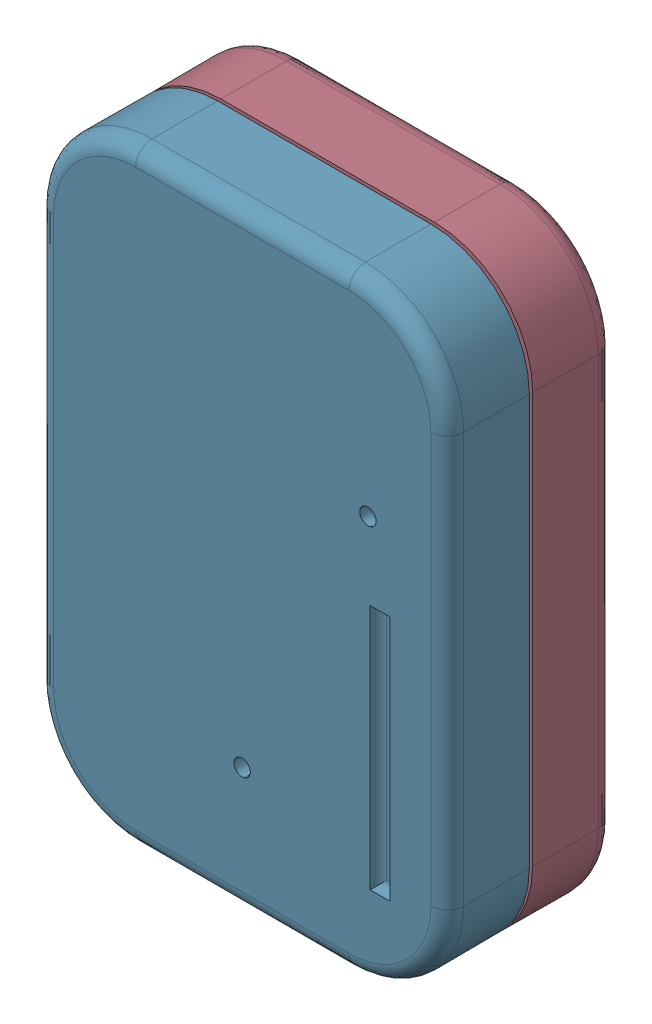
SolidWorks assembly ASSEMBLY, configuration Default. Lengths in mm.
Overall size (24.97 36.97 10.2).
67 component instances, 15 part files, 0 mates.
Components (placement in the parent):
- 3D_End Device_2025-10-05.step-1: 3D_End Device_2025-10-05.step [Default] at (-3.1574 34.3735 25.9804) size (20.97 32.97 10.2)
  - L1~L0402~L0402_L1.0-W0.5-H0.5_BEAD~bX66.step-1: L1~L0402~L0402_L1.0-W0.5-H0.5_BEAD~bX66.step [Default] at (9.437 -12.392 1.6001) x (0 1 0) z (0 0 1) size (0.76 0.76 0.76)
    - L2~L0402~L0402_L1.0-W0.5-H0.5_BEAD~bX66.step-1: L2~L0402~L0402_L1.0-W0.5-H0.5_BEAD~bX66.step [Default] at origin size (0.76 0.76 0.76)
  - X1~CRYSTAL-SMD_4P-L3.2-W2.5-BL~CRYSTAL-SMD_4P-L3.2-W2.5-BL_SIT8008BI~bX66.step-1: X1~CRYSTAL-SMD_4P-L3.2-W2.5-BL~CRYSTAL-SMD_4P-L3.2-W2.5-BL_SIT8008BI~bX66.step [Default] at (13.7334 -14.7376 1.6001) x (0 1 0) z (0 0 1) size (0.76 0.76 0.76)
    - CRYSTAL-SMD_4P-L3.2-W2.5-BL~CRYSTAL-SMD_4P-L3.2-W2.5-BL_SIT8008BI~bX66.step-1: CRYSTAL-SMD_4P-L3.2-W2.5-BL~CRYSTAL-SMD_4P-L3.2-W2.5-BL_SIT8008BI~bX66.step [Default] at origin size (0.76 0.76 0.76)
  - R1~R0402~R0402_L1.0-W0.5-H0.4~bX66.step-1: R1~R0402~R0402_L1.0-W0.5-H0.4~bX66.step [Default] at (4.7194 -17.5106 1.6001) x (0 1 0) z (0 0 1) size (0.76 0.76 0.76)
    - R5~R0402~R0402_L1.0-W0.5-H0.4~bX66.step-1: R5~R0402~R0402_L1.0-W0.5-H0.4~bX66.step [Default] at origin size (0.76 0.76 0.76)
  - BT1~BAT-SMD_MY-2032-12~BAT-SMD_MY-2032-12~bX66.step-1: BT1~BAT-SMD_MY-2032-12~BAT-SMD_MY-2032-12~bX66.step [Default] at (10.502 -19.933 0) x (0 1 0) z (0 0 -1) size (24.1 15.69 3.6)
    - BAT-SMD_MY-2032-12~BAT-SMD_MY-2032-12~bX66.step-1: BAT-SMD_MY-2032-12~BAT-SMD_MY-2032-12~bX66.step [Default] at origin size (24.1 15.69 3.6)
  - C1~C0402~C0402_L1.0-W0.5-H0.5~bX66.step-1: C1~C0402~C0402_L1.0-W0.5-H0.5~bX66.step [Default] at (14.0762 -17.6973 1.6001) size (1 0.5 0.5)
    - C0402~C0402_L1.0-W0.5-H0.5~bX66.step-1: C0402~C0402_L1.0-W0.5-H0.5~bX66.step [Default] at origin size (1 0.5 0.5)
  - C1~C0402~C0402_L1.0-W0.5-H0.5~bX66.step-2: C1~C0402~C0402_L1.0-W0.5-H0.5~bX66.step [Default] at (13.4642 -11.9342 1.6001) x (-1 0 0) z (0 0 1) size (1 0.5 0.5)
    - C0402~C0402_L1.0-W0.5-H0.5~bX66.step-1: C0402~C0402_L1.0-W0.5-H0.5~bX66.step [Default] at origin size (1 0.5 0.5)
  - C1~C0402~C0402_L1.0-W0.5-H0.5~bX66.step-3: C1~C0402~C0402_L1.0-W0.5-H0.5~bX66.step [Default] at (9.4954 -16.5416 1.6001) x (0 1 0) z (0 0 1) size (1 0.5 0.5)
    - C0402~C0402_L1.0-W0.5-H0.5~bX66.step-1: C0402~C0402_L1.0-W0.5-H0.5~bX66.step [Default] at origin size (1 0.5 0.5)
  - C1~C0402~C0402_L1.0-W0.5-H0.5~bX66.step-4: C1~C0402~C0402_L1.0-W0.5-H0.5~bX66.step [Default] at (8.3014 -16.5416 1.6001) x (0 1 0) z (0 0 1) size (1 0.5 0.5)
    - C0402~C0402_L1.0-W0.5-H0.5~bX66.step-1: C0402~C0402_L1.0-W0.5-H0.5~bX66.step [Default] at origin size (1 0.5 0.5)
  - C1~C0402~C0402_L1.0-W0.5-H0.5~bX66.step-5: C1~C0402~C0402_L1.0-W0.5-H0.5~bX66.step [Default] at (10.6082 -12.3932 1.6001) x (0 -1 0) z (0 0 1) size (1 0.5 0.5)
    - C0402~C0402_L1.0-W0.5-H0.5~bX66.step-1: C0402~C0402_L1.0-W0.5-H0.5~bX66.step [Default] at origin size (1 0.5 0.5)
  - C1~C0402~C0402_L1.0-W0.5-H0.5~bX66.step-6: C1~C0402~C0402_L1.0-W0.5-H0.5~bX66.step [Default] at (8.8094 -10.4456 1.6001) x (-1 0 0) z (0 0 1) size (1 0.5 0.5)
    - C0402~C0402_L1.0-W0.5-H0.5~bX66.step-1: C0402~C0402_L1.0-W0.5-H0.5~bX66.step [Default] at origin size (1 0.5 0.5)
  - C1~C0402~C0402_L1.0-W0.5-H0.5~bX66.step-7: C1~C0402~C0402_L1.0-W0.5-H0.5~bX66.step [Default] at (8.802 -9.217 1.6001) x (-1 0 0) z (0 0 1) size (1 0.5 0.5)
    - C0402~C0402_L1.0-W0.5-H0.5~bX66.step-1: C0402~C0402_L1.0-W0.5-H0.5~bX66.step [Default] at origin size (1 0.5 0.5)
  - C1~C0402~C0402_L1.0-W0.5-H0.5~bX66.step-8: C1~C0402~C0402_L1.0-W0.5-H0.5~bX66.step [Default] at (3.9665 -14.0976 1.6001) size (1 0.5 0.5)
    - C0402~C0402_L1.0-W0.5-H0.5~bX66.step-1: C0402~C0402_L1.0-W0.5-H0.5~bX66.step [Default] at origin size (1 0.5 0.5)
  - C1~C0402~C0402_L1.0-W0.5-H0.5~bX66.step-9: C1~C0402~C0402_L1.0-W0.5-H0.5~bX66.step [Default] at (3.9665 -8.2555 1.6001) size (1 0.5 0.5)
    - C0402~C0402_L1.0-W0.5-H0.5~bX66.step-1: C0402~C0402_L1.0-W0.5-H0.5~bX66.step [Default] at origin size (1 0.5 0.5)
  - C1~C0402~C0402_L1.0-W0.5-H0.5~bX66.step-10: C1~C0402~C0402_L1.0-W0.5-H0.5~bX66.step [Default] at (3.722 -23.187 1.6001) x (-1 0 0) z (0 0 1) size (1 0.5 0.5)
    - C0402~C0402_L1.0-W0.5-H0.5~bX66.step-1: C0402~C0402_L1.0-W0.5-H0.5~bX66.step [Default] at origin size (1 0.5 0.5)
  - C1~C0402~C0402_L1.0-W0.5-H0.5~bX66.step-11: C1~C0402~C0402_L1.0-W0.5-H0.5~bX66.step [Default] at (13.7192 -24.8884 1.6001) x (-1 0 0) z (0 0 1) size (1 0.5 0.5)
    - C0402~C0402_L1.0-W0.5-H0.5~bX66.step-1: C0402~C0402_L1.0-W0.5-H0.5~bX66.step [Default] at origin size (1 0.5 0.5)
  - C1~C0402~C0402_L1.0-W0.5-H0.5~bX66.step-12: C1~C0402~C0402_L1.0-W0.5-H0.5~bX66.step [Default] at (13.6354 -19.2086 1.6001) x (-1 0 0) z (0 0 1) size (1 0.5 0.5)
    - C0402~C0402_L1.0-W0.5-H0.5~bX66.step-1: C0402~C0402_L1.0-W0.5-H0.5~bX66.step [Default] at origin size (1 0.5 0.5)
  - C1~C0402~C0402_L1.0-W0.5-H0.5~bX66.step-13: C1~C0402~C0402_L1.0-W0.5-H0.5~bX66.step [Default] at (10.6894 -16.5416 1.6001) x (0 -1 0) z (0 0 1) size (1 0.5 0.5)
    - C0402~C0402_L1.0-W0.5-H0.5~bX66.step-1: C0402~C0402_L1.0-W0.5-H0.5~bX66.step [Default] at origin size (1 0.5 0.5)
  - C1~C0402~C0402_L1.0-W0.5-H0.5~bX66.step-14: C1~C0402~C0402_L1.0-W0.5-H0.5~bX66.step [Default] at (5.9134 -16.5416 1.6001) x (0 -1 0) z (0 0 1) size (1 0.5 0.5)
    - C0402~C0402_L1.0-W0.5-H0.5~bX66.step-1: C0402~C0402_L1.0-W0.5-H0.5~bX66.step [Default] at origin size (1 0.5 0.5)
  - C1~C0402~C0402_L1.0-W0.5-H0.5~bX66.step-15: C1~C0402~C0402_L1.0-W0.5-H0.5~bX66.step [Default] at (7.1074 -16.5416 1.6001) x (0 -1 0) z (0 0 1) size (1 0.5 0.5)
    - C0402~C0402_L1.0-W0.5-H0.5~bX66.step-1: C0402~C0402_L1.0-W0.5-H0.5~bX66.step [Default] at origin size (1 0.5 0.5)
  - C1~C0402~C0402_L1.0-W0.5-H0.5~bX66.step-16: C1~C0402~C0402_L1.0-W0.5-H0.5~bX66.step [Default] at (3.5191 -18.5643 1.6001) x (0 -1 0) z (0 0 1) size (1 0.5 0.5)
    - C0402~C0402_L1.0-W0.5-H0.5~bX66.step-1: C0402~C0402_L1.0-W0.5-H0.5~bX66.step [Default] at origin size (1 0.5 0.5)
  - C1~C0402~C0402_L1.0-W0.5-H0.5~bX66.step-17: C1~C0402~C0402_L1.0-W0.5-H0.5~bX66.step [Default] at (3.087 -25.092 1.6001) x (0 1 0) z (0 0 1) size (1 0.5 0.5)
    - C0402~C0402_L1.0-W0.5-H0.5~bX66.step-1: C0402~C0402_L1.0-W0.5-H0.5~bX66.step [Default] at origin size (1 0.5 0.5)
  - C1~C0402~C0402_L1.0-W0.5-H0.5~bX66.step-18: C1~C0402~C0402_L1.0-W0.5-H0.5~bX66.step [Default] at (4.3644 -25.0506 1.6001) x (0 1 0) z (0 0 1) size (1 0.5 0.5)
    - C0402~C0402_L1.0-W0.5-H0.5~bX66.step-1: C0402~C0402_L1.0-W0.5-H0.5~bX66.step [Default] at origin size (1 0.5 0.5)
  - JP1~RF-SMD_FRF05002-JSS103M~RF-SMD_FRF05002-JSS103M~bX66.step-1: JP1~RF-SMD_FRF05002-JSS103M~RF-SMD_FRF05002-JSS103M~bX66.step [Default] at (13.2092 -7.9561 1.6001) x (-1 0 0) z (0 0 1) size (3 3.1 1.25)
    - RF-SMD_FRF05002-JSS103M~RF-SMD_FRF05002-JSS103M~bX66.step-1: RF-SMD_FRF05002-JSS103M~RF-SMD_FRF05002-JSS103M~bX66.step [Default] at origin size (3 3.1 1.25)
  - LED1~LED0402-R-RD~LED0402_L1.0-W0.5-H0.4~bX66.step-1: LED1~LED0402-R-RD~LED0402_L1.0-W0.5-H0.4~bX66.step [Default] at (10.5 -27.4384 1.6001) size (1.02 0.51 0.41)
    - LED0402-R-RD~LED0402_L1.0-W0.5-H0.4~bX66.step-1: LED0402-R-RD~LED0402_L1.0-W0.5-H0.4~bX66.step [Default] at origin size (1.02 0.51 0.41)
  - U1~QFN-40_L6.0-W6.0-P0.50-TL-EP4.1~TQFN-40_L6.0-W6.0-P0.50-TL-EP4.1~bX66.step-1: U1~QFN-40_L6.0-W6.0-P0.50-TL-EP4.1~TQFN-40_L6.0-W6.0-P0.50-TL-EP4.1~bX66.step [Default] at (8.6917 -21.9164 1.6001) x (0 1 0) z (0 0 1) size (6.02 6.02 0.76)
    - QFN-40_L6.0-W6.0-P0.50-TL-EP4.1~TQFN-40_L6.0-W6.0-P0.50-TL-EP4.1~bX66.step-1: QFN-40_L6.0-W6.0-P0.50-TL-EP4.1~TQFN-40_L6.0-W6.0-P0.50-TL-EP4.1~bX66.step [Default] at origin size (6.02 6.02 0.76)
  - X2~OSC-SMD_L3.2-W1.5~OSC-SMD_L3.2-W1.5-H0.8~bX66.step-1: X2~OSC-SMD_L3.2-W1.5~OSC-SMD_L3.2-W1.5-H0.8~bX66.step [Default] at (3.9665 -11.1766 1.6001) x (0 1 0) z (0 0 1) size (3.2 1.5 0.8)
    - OSC-SMD_L3.2-W1.5~OSC-SMD_L3.2-W1.5-H0.8~bX66.step-1: OSC-SMD_L3.2-W1.5~OSC-SMD_L3.2-W1.5-H0.8~bX66.step [Default] at origin size (3.2 1.5 0.8)
  - U4~CONN-SMD_C9900014775~CONN-SMD_C9900014775~bX66.step-1: U4~CONN-SMD_C9900014775~CONN-SMD_C9900014775~bX66.step [Default] at (8.2111 -29.6314 1.6001) x (-1 0 0) z (0 0 1) size (12.8 2.5 5) (hidden)
    - CONN-SMD_C9900014775~CONN-SMD_C9900014775~bX66.step-1: CONN-SMD_C9900014775~CONN-SMD_C9900014775~bX66.step [Default] at origin size (12.8 2.5 5)
  - SW1~SW-SMD_4P-L3.4-W3.4-P2.00-LS4.0_YTSA007AXXXX~SW-SMD_4P-L3.4-W3.4-P2.00-LS4.0_YTSA007AXXXX~bX66.step-1: SW1~SW-SMD_4P-L3.4-W3.4-P2.00-LS4.0_YTSA007AXXXX~SW-SMD_4P-L3.4-W3.4-P2.00-LS4.0_YTSA007AXXXX~bX66.step [Default] at (18.1563 -10.3532 1.6001) x (0 1 0) z (0 0 1) size (3.95 3.43 2)
    - SW-SMD_4P-L3.4-W3.4-P2.00-LS4.0_YTSA007AXXXX~SW-SMD_4P-L3.4-W3.4-P2.00-LS4.0_YTSA007AXXXX~bX66.step-1: SW-SMD_4P-L3.4-W3.4-P2.00-LS4.0_YTSA007AXXXX~SW-SMD_4P-L3.4-W3.4-P2.00-LS4.0_YTSA007AXXXX~bX66.step [Default] at origin size (3.95 3.43 2)
  - U2~SENSOR-SMD_59170-1-S-00-D~SENSOR-SMD_L11.4-W2.3-H2.3-59170-1-S-00-D~bX66.step-1: U2~SENSOR-SMD_59170-1-S-00-D~SENSOR-SMD_L11.4-W2.3-H2.3-59170-1-S-00-D~bX66.step [Default] at (18.4623 -22.4403 1.6001) x (0 -1 0) z (0 0 1) size (0.76 0.76 0.76)
    - SENSOR-SMD_59170-1-S-00-D~SENSOR-SMD_L11.4-W2.3-H2.3-59170-1-S-00-D~bX66.step-1: SENSOR-SMD_59170-1-S-00-D~SENSOR-SMD_L11.4-W2.3-H2.3-59170-1-S-00-D~bX66.step [Default] at origin size (0.76 0.76 0.76)
  - Board~bX66.step-1: Board~bX66.step [Default] at origin size (20.97 32.97 1.6)
  - L2~L0402~L0402_L1.0-W0.5-H0.5_BEAD~bX66.step-1: L2~L0402~L0402_L1.0-W0.5-H0.5_BEAD~bX66.step [Default] at (7.532 -12.392 1.6001) x (-1 0 0) z (0 0 1) size (0.76 0.76 0.76)
  - R5~R0402~R0402_L1.0-W0.5-H0.4~bX66.step-1: R5~R0402~R0402_L1.0-W0.5-H0.4~bX66.step [Default] at (13.6951 -20.4168 1.6001) x (-1 0 0) z (0 0 1) size (0.76 0.76 0.76)
  - R5~R0402~R0402_L1.0-W0.5-H0.4~bX66.step-2: R5~R0402~R0402_L1.0-W0.5-H0.4~bX66.step [Default] at (10.857 -26.1124 1.6001) x (-1 0 0) z (0 0 1) size (0.76 0.76 0.76)
  - R5~R0402~R0402_L1.0-W0.5-H0.4~bX66.step-3: R5~R0402~R0402_L1.0-W0.5-H0.4~bX66.step [Default] at (6.0691 -8.7721 1.6001) x (0 1 0) z (0 0 1) size (0.76 0.76 0.76)
  - R5~R0402~R0402_L1.0-W0.5-H0.4~bX66.step-4: R5~R0402~R0402_L1.0-W0.5-H0.4~bX66.step [Default] at (8.2621 -7.4461 1.6001) x (0 1 0) z (0 0 1) size (0.76 0.76 0.76)
- COVER BOTTOM-1: COVER BOTTOM [Default] at origin size (24.97 36.97 7.5)
- COVER UPPER-1: COVER UPPER [Default] at (0.0062 -0.0273 -0.0423) size (24.97 36.97 5)
